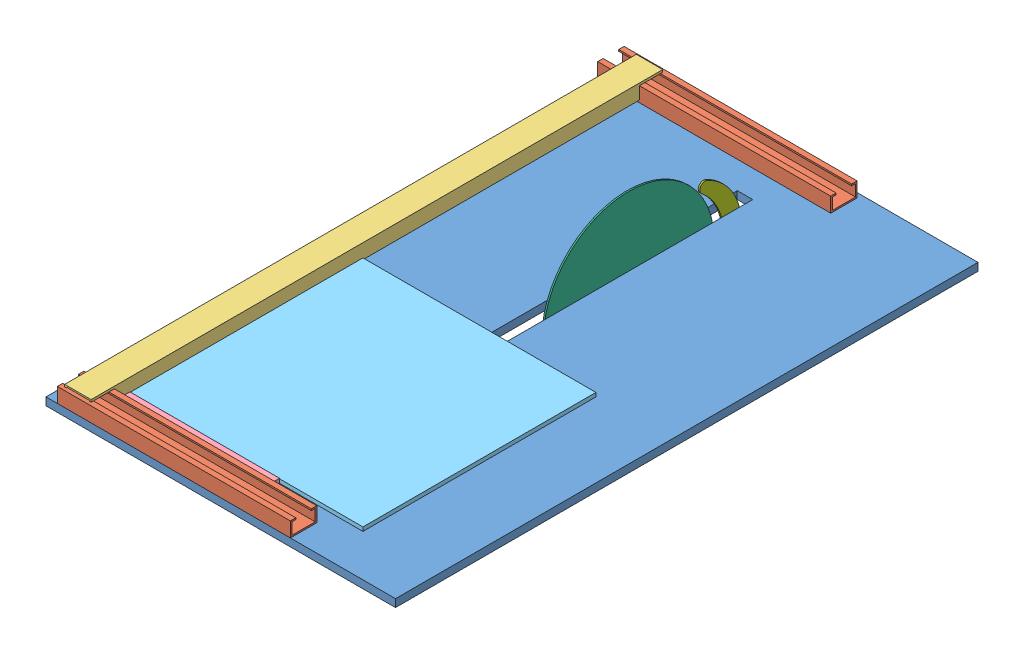
SolidWorks assembly Фстол, configuration По умолчанию. Lengths in mm.
Overall size (450 220 750).
9 component instances, 7 part files, 17 mates.
Components (placement in the parent):
- Стол-1: Стол [По умолчанию] at origin size (450 10 750)
- Направляющая-1: Направляющая [По умолчанию] at (-224.653 12 -352) size (300 19 34)
- Направляющая-2: Направляющая [По умолчанию] at (-210.3457 12 358) size (300 19 34)
- Направляющая1-1: Направляющая1 [По умолчанию] at (-187.924 30 371) x (0 0 -1) z (-1 0 0) size (736 19 34)
- Упор-1: Упор [По умолчанию] at (21.6127 15.5979 341) x (0 0 -1) z (0 1 0) size (20 200 5.6)
- Плитка-1: Плитка [По умолчанию] at (-170.924 10 21) size (300 5 300)
- Пила-1: Пила [По умолчанию] at (4 -14.3624 -152.0428) x (0 0 -1) z (1 0 0) size (254.78 220 2)
  - Диск-1: Диск [По умолчанию] at (-7.8009 -0.6376 0) x (0 0 1) z (-1 0 0) size (2 220 220)
  - защита-1: защита [По умолчанию] at (127.1426 -4.543 0) size (53.27 83.27 2)
Mates (geometry in assembly coordinates):
- Совпадение1: coincident: plane of Стол-1 through (0 10 0) normal (0 1 0); plane of Направляющая-1 through (75.347 10 -337) normal (0 -1 0)
- Параллельность1: parallel: plane of Стол-1 through (-225 10 -375) normal (0 0 -1); plane of Направляющая-1 through (75.347 12 -369) normal (0 0 -1)
- Совпадение4: coincident: plane of Стол-1 through (0 10 0) normal (0 1 0); plane of Направляющая-2 through (89.6543 10 373) normal (0 -1 0)
- Совпадение25: coincident: plane of Стол-1 through (-225 10 375) normal (0 0 1); plane of Направляющая-2 through (89.6543 12 375) normal (0 0 1)
- Параллельность6: parallel: plane of Стол-1 through (-225 10 375) normal (-1 0 0); plane of Направляющая1-1 through (-204.924 30 -365) normal (-1 0 0)
- Параллельность7: parallel: plane of Направляющая-1 through (75.347 29 -337) normal (0 1 0); plane of Направляющая1-1 through (-204.924 29 -365) normal (0 -1 0)
- Совпадение17: coincident: plane of Направляющая-1 through (75.347 29 -337) normal (0 1 0); plane of Направляющая1-1 through (-204.924 29 -365) normal (0 -1 0)
- Совпадение18: coincident: plane of Стол-1 through (0 10 0) normal (0 1 0); plane of Упор-1 through (-178.3873 10 341) normal (0 -1 0)
- Совпадение19: coincident: plane of Направляющая-2 through (89.6543 12 341) normal (0 0 -1); plane of Упор-1 through (-178.3873 10 341) normal (0 0 1)
- Совпадение20: coincident: plane of Направляющая-1 through (75.347 12 -335) normal (0 0 1); plane of Направляющая1-1 through (-204.924 13 -335) normal (0 0 -1)
- Совпадение21: coincident: plane of Направляющая-2 through (89.6543 12 341) normal (0 0 -1); plane of Направляющая1-1 through (-204.924 13 341) normal (0 0 1)
- Совпадение22: coincident: plane of Стол-1 through (0 10 0) normal (0 1 0); plane of Плитка-1 through (-170.924 10 21) normal (0 -1 0)
- Совпадение23: coincident: plane of Упор-1 through (-178.3873 10 321) normal (0 0 -1); plane of Плитка-1 through (-170.924 15 321) normal (0 0 1)
- Совпадение24: coincident: plane of Направляющая1-1 through (-170.924 30 -365) normal (1 0 0); plane of Плитка-1 through (-170.924 15 21) normal (-1 0 0)
- Расстояние2: distance = 4 mm: plane of Пила-1/Диск-1 through (6 -15 -144.242) normal (1 0 0); plane of Стол-1 through (10 10 -300) normal (-1 0 0)
- Расстояние3: distance = 5 mm: cylinder of Пила-1/Диск-1 through (6 -15 -144.242) axis (-1 0 0) radius 10; plane of Стол-1 through (0 0 0) normal (0 -1 0)
- Параллельность9: parallel: plane of Стол-1 through (0 0 0) normal (0 -1 0); plane of Пила-1/защита-1 through (6 -25.8331 -265.1518) normal (0 -1 0)
